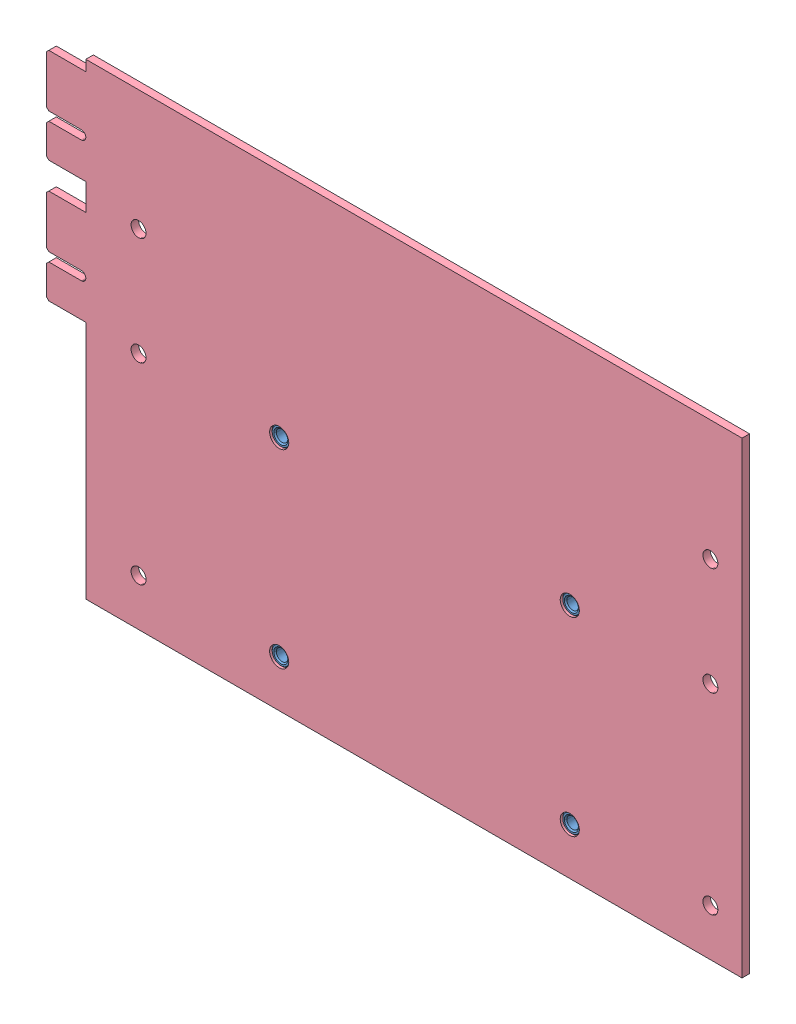
SolidWorks assembly EKO_Miner_BM1366 PCBonly, configuration Défaut. Lengths in mm.
Overall size (148.4 99.75 4.88).
82 component instances, 4 part files, 0 mates.
Components (placement in the parent):
- EKO_Miner_BM1366 PCBonly.step-1: EKO_Miner_BM1366 PCBonly.step [Défaut] at origin size (148.4 99.75 4.88)
  - SMTSO-M3-3ET.step-1: SMTSO-M3-3ET.step [Défaut] at (178 -115 1.25) x (0 0 -1) z (1 0 0) size (4.53 5.56 5.56)
    - 1.step-1: 1.step [Défaut] at origin size (4.53 5.56 5.56)
  - CP_EIA-7343-31_Kemet-D.step-1: CP_EIA-7343-31_Kemet-D.step [Défaut] at (138.6707 -104.934 -0.05) x (0 1 0) z (0 0 -1) size (7.3 4.3 3.1)
    - CP_EIA_7343_31_Kemet_D.step-1: CP_EIA_7343_31_Kemet_D.step [Défaut] at origin size (7.3 4.3 3.1)
  - C_1210_3225Metric.step-1: C_1210_3225Metric.step [Défaut] at (111.58 -61.5 -0.05) x (1 0 0) z (0 0 -1) size (3.2 2.5 2.5)
    - C_1210_3225Metric-1.step-1: C_1210_3225Metric-1.step [Défaut] at origin size (3.2 2.5 2.5)
  - C_1210_3225Metric.step-2: C_1210_3225Metric.step [Défaut] at (111.58 -68.104 -0.05) x (1 0 0) z (0 0 -1) size (3.2 2.5 2.5)
    - C_1210_3225Metric-1.step-1: C_1210_3225Metric-1.step [Défaut] at origin size (3.2 2.5 2.5)
  - CP_EIA-7343-31_Kemet-D.step-2: CP_EIA-7343-31_Kemet-D.step [Défaut] at (90.498 -84.106 -0.05) x (0 -1 0) z (0 0 -1) size (7.3 4.3 3.1)
    - CP_EIA_7343_31_Kemet_D.step-1: CP_EIA_7343_31_Kemet_D.step [Défaut] at origin size (7.3 4.3 3.1)
  - C_1210_3225Metric.step-3: C_1210_3225Metric.step [Défaut] at (208.98 -64.802 -0.05) x (1 0 0) z (0 0 -1) size (3.2 2.5 2.5)
    - C_1210_3225Metric-1.step-1: C_1210_3225Metric-1.step [Défaut] at origin size (3.2 2.5 2.5)
  - C_1210_3225Metric.step-4: C_1210_3225Metric.step [Défaut] at (144.0467 -61.5 -0.05) x (1 0 0) z (0 0 -1) size (3.2 2.5 2.5)
    - C_1210_3225Metric-1.step-1: C_1210_3225Metric-1.step [Défaut] at origin size (3.2 2.5 2.5)
  - C_1210_3225Metric.step-5: C_1210_3225Metric.step [Défaut] at (208.98 -58.2047 -0.05) x (1 0 0) z (0 0 -1) size (3.2 2.5 2.5)
    - C_1210_3225Metric-1.step-1: C_1210_3225Metric-1.step [Défaut] at origin size (3.2 2.5 2.5)
  - CP_EIA-7343-31_Kemet-D.step-3: CP_EIA-7343-31_Kemet-D.step [Défaut] at (154.9414 -84.106 -0.05) x (0 -1 0) z (0 0 -1) size (7.3 4.3 3.1)
    - CP_EIA_7343_31_Kemet_D.step-1: CP_EIA_7343_31_Kemet_D.step [Défaut] at origin size (7.3 4.3 3.1)
  - C_1210_3225Metric.step-6: C_1210_3225Metric.step [Défaut] at (144.0467 -64.802 -0.05) x (1 0 0) z (0 0 -1) size (3.2 2.5 2.5)
    - C_1210_3225Metric-1.step-1: C_1210_3225Metric-1.step [Défaut] at origin size (3.2 2.5 2.5)
  - CP_EIA-7343-31_Kemet-D.step-4: CP_EIA-7343-31_Kemet-D.step [Défaut] at (90.498 -104.934 -0.05) x (0 1 0) z (0 0 -1) size (7.3 4.3 3.1)
    - CP_EIA_7343_31_Kemet_D.step-1: CP_EIA_7343_31_Kemet_D.step [Défaut] at origin size (7.3 4.3 3.1)
  - C_1210_3225Metric.step-7: C_1210_3225Metric.step [Défaut] at (208.98 -61.5 -0.05) x (1 0 0) z (0 0 -1) size (3.2 2.5 2.5)
    - C_1210_3225Metric-1.step-1: C_1210_3225Metric-1.step [Défaut] at origin size (3.2 2.5 2.5)
  - CP_EIA-7343-31_Kemet-D.step-5: CP_EIA-7343-31_Kemet-D.step [Défaut] at (202.512 -104.934 -0.05) x (0 1 0) z (0 0 -1) size (7.3 4.3 3.1)
    - CP_EIA_7343_31_Kemet_D.step-1: CP_EIA_7343_31_Kemet_D.step [Défaut] at origin size (7.3 4.3 3.1)
  - SMTSO-M3-3ET.step-2: SMTSO-M3-3ET.step [Défaut] at (116 -74.5 1.25) x (0 0 -1) z (1 0 0) size (4.53 5.56 5.56)
    - 1.step-1: 1.step [Défaut] at origin size (4.53 5.56 5.56)
  - CP_EIA-7343-31_Kemet-D.step-6: CP_EIA-7343-31_Kemet-D.step [Défaut] at (186.51 -104.934 -0.05) x (0 1 0) z (0 0 -1) size (7.3 4.3 3.1)
    - CP_EIA_7343_31_Kemet_D.step-1: CP_EIA_7343_31_Kemet_D.step [Défaut] at origin size (7.3 4.3 3.1)
  - CP_EIA-7343-31_Kemet-D.step-7: CP_EIA-7343-31_Kemet-D.step [Défaut] at (154.6727 -104.934 -0.05) x (0 1 0) z (0 0 -1) size (7.3 4.3 3.1)
    - CP_EIA_7343_31_Kemet_D.step-1: CP_EIA_7343_31_Kemet_D.step [Défaut] at origin size (7.3 4.3 3.1)
  - C_1210_3225Metric.step-8: C_1210_3225Metric.step [Défaut] at (144.0467 -58.2047 -0.05) x (1 0 0) z (0 0 -1) size (3.2 2.5 2.5)
    - C_1210_3225Metric-1.step-1: C_1210_3225Metric-1.step [Défaut] at origin size (3.2 2.5 2.5)
  - CP_EIA-7343-31_Kemet-D.step-8: CP_EIA-7343-31_Kemet-D.step [Défaut] at (122.502 -104.934 -0.05) x (0 1 0) z (0 0 -1) size (7.3 4.3 3.1)
    - CP_EIA_7343_31_Kemet_D.step-1: CP_EIA_7343_31_Kemet_D.step [Défaut] at origin size (7.3 4.3 3.1)
  - CP_EIA-7343-31_Kemet-D.step-9: CP_EIA-7343-31_Kemet-D.step [Défaut] at (138.758 -84.106 -0.05) x (0 -1 0) z (0 0 -1) size (7.3 4.3 3.1)
    - CP_EIA_7343_31_Kemet_D.step-1: CP_EIA_7343_31_Kemet_D.step [Défaut] at origin size (7.3 4.3 3.1)
  - CP_EIA-7343-31_Kemet-D.step-10: CP_EIA-7343-31_Kemet-D.step [Défaut] at (168.0833 -58.8 -0.05) x (-1 0 0) z (0 0 -1) size (7.3 4.3 3.1)
    - CP_EIA_7343_31_Kemet_D.step-1: CP_EIA_7343_31_Kemet_D.step [Défaut] at origin size (7.3 4.3 3.1)
  - CP_EIA-7343-31_Kemet-D.step-11: CP_EIA-7343-31_Kemet-D.step [Défaut] at (103.15 -58.8 -0.05) x (-1 0 0) z (0 0 -1) size (7.3 4.3 3.1)
    - CP_EIA_7343_31_Kemet_D.step-1: CP_EIA_7343_31_Kemet_D.step [Défaut] at origin size (7.3 4.3 3.1)
  - C_1210_3225Metric.step-9: C_1210_3225Metric.step [Défaut] at (176.5133 -61.5 -0.05) x (1 0 0) z (0 0 -1) size (3.2 2.5 2.5)
    - C_1210_3225Metric-1.step-1: C_1210_3225Metric-1.step [Défaut] at origin size (3.2 2.5 2.5)
  - CP_EIA-7343-31_Kemet-D.step-12: CP_EIA-7343-31_Kemet-D.step [Défaut] at (171.0523 -84.106 -0.05) x (0 -1 0) z (0 0 -1) size (7.3 4.3 3.1)
    - CP_EIA_7343_31_Kemet_D.step-1: CP_EIA_7343_31_Kemet_D.step [Défaut] at origin size (7.3 4.3 3.1)
  - CP_EIA-7343-31_Kemet-D.step-13: CP_EIA-7343-31_Kemet-D.step [Défaut] at (200.55 -58.8 -0.05) x (-1 0 0) z (0 0 -1) size (7.3 4.3 3.1)
    - CP_EIA_7343_31_Kemet_D.step-1: CP_EIA_7343_31_Kemet_D.step [Défaut] at origin size (7.3 4.3 3.1)
  - CP_EIA-7343-31_Kemet-D.step-14: CP_EIA-7343-31_Kemet-D.step [Défaut] at (106.5 -104.934 -0.05) x (0 1 0) z (0 0 -1) size (7.3 4.3 3.1)
    - CP_EIA_7343_31_Kemet_D.step-1: CP_EIA_7343_31_Kemet_D.step [Défaut] at origin size (7.3 4.3 3.1)
  - C_1210_3225Metric.step-10: C_1210_3225Metric.step [Défaut] at (176.5133 -58.2047 -0.05) x (1 0 0) z (0 0 -1) size (3.2 2.5 2.5)
    - C_1210_3225Metric-1.step-1: C_1210_3225Metric-1.step [Défaut] at origin size (3.2 2.5 2.5)
  - C_1210_3225Metric.step-11: C_1210_3225Metric.step [Défaut] at (208.98 -68.104 -0.05) x (1 0 0) z (0 0 -1) size (3.2 2.5 2.5)
    - C_1210_3225Metric-1.step-1: C_1210_3225Metric-1.step [Défaut] at origin size (3.2 2.5 2.5)
  - CP_EIA-7343-31_Kemet-D.step-15: CP_EIA-7343-31_Kemet-D.step [Défaut] at (135.6167 -58.8 -0.05) x (-1 0 0) z (0 0 -1) size (7.3 4.3 3.1)
    - CP_EIA_7343_31_Kemet_D.step-1: CP_EIA_7343_31_Kemet_D.step [Défaut] at origin size (7.3 4.3 3.1)
  - CP_EIA-7343-31_Kemet-D.step-16: CP_EIA-7343-31_Kemet-D.step [Défaut] at (106.6089 -84.106 -0.05) x (0 -1 0) z (0 0 -1) size (7.3 4.3 3.1)
    - CP_EIA_7343_31_Kemet_D.step-1: CP_EIA_7343_31_Kemet_D.step [Défaut] at origin size (7.3 4.3 3.1)
  - SMTSO-M3-3ET.step-3: SMTSO-M3-3ET.step [Défaut] at (116 -115 1.25) x (0 0 -1) z (1 0 0) size (4.53 5.56 5.56)
    - 1.step-1: 1.step [Défaut] at origin size (4.53 5.56 5.56)
  - CP_EIA-7343-31_Kemet-D.step-17: CP_EIA-7343-31_Kemet-D.step [Défaut] at (122.756 -84.106 -0.05) x (0 -1 0) z (0 0 -1) size (7.3 4.3 3.1)
    - CP_EIA_7343_31_Kemet_D.step-1: CP_EIA_7343_31_Kemet_D.step [Défaut] at origin size (7.3 4.3 3.1)
  - SMTSO-M3-3ET.step-4: SMTSO-M3-3ET.step [Défaut] at (178 -74.5 1.25) x (0 0 -1) z (1 0 0) size (4.53 5.56 5.56)
    - 1.step-1: 1.step [Défaut] at origin size (4.53 5.56 5.56)
  - C_1210_3225Metric.step-12: C_1210_3225Metric.step [Défaut] at (111.58 -58.198 -0.05) x (1 0 0) z (0 0 -1) size (3.2 2.5 2.5)
    - C_1210_3225Metric-1.step-1: C_1210_3225Metric-1.step [Défaut] at origin size (3.2 2.5 2.5)
  - CP_EIA-7343-31_Kemet-D.step-18: CP_EIA-7343-31_Kemet-D.step [Défaut] at (187.2715 -84.086 -0.05) x (0 -1 0) z (0 0 -1) size (7.3 4.3 3.1)
    - CP_EIA_7343_31_Kemet_D.step-1: CP_EIA_7343_31_Kemet_D.step [Défaut] at origin size (7.3 4.3 3.1)
  - CP_EIA-7343-31_Kemet-D.step-19: CP_EIA-7343-31_Kemet-D.step [Défaut] at (203.274 -84.106 -0.05) x (0 -1 0) z (0 0 -1) size (7.3 4.3 3.1)
    - CP_EIA_7343_31_Kemet_D.step-1: CP_EIA_7343_31_Kemet_D.step [Défaut] at origin size (7.3 4.3 3.1)
  - C_1210_3225Metric.step-13: C_1210_3225Metric.step [Défaut] at (176.5133 -64.802 -0.05) x (1 0 0) z (0 0 -1) size (3.2 2.5 2.5)
    - C_1210_3225Metric-1.step-1: C_1210_3225Metric-1.step [Défaut] at origin size (3.2 2.5 2.5)
  - CP_EIA-7343-31_Kemet-D.step-20: CP_EIA-7343-31_Kemet-D.step [Défaut] at (170.508 -104.934 -0.05) x (0 1 0) z (0 0 -1) size (7.3 4.3 3.1)
    - CP_EIA_7343_31_Kemet_D.step-1: CP_EIA_7343_31_Kemet_D.step [Défaut] at origin size (7.3 4.3 3.1)
  - C_1210_3225Metric.step-14: C_1210_3225Metric.step [Défaut] at (176.5133 -68.104 -0.05) x (1 0 0) z (0 0 -1) size (3.2 2.5 2.5)
    - C_1210_3225Metric-1.step-1: C_1210_3225Metric-1.step [Défaut] at origin size (3.2 2.5 2.5)
  - C_1210_3225Metric.step-15: C_1210_3225Metric.step [Défaut] at (144.0467 -68.104 -0.05) x (1 0 0) z (0 0 -1) size (3.2 2.5 2.5)
    - C_1210_3225Metric-1.step-1: C_1210_3225Metric-1.step [Défaut] at origin size (3.2 2.5 2.5)
  - C_1210_3225Metric.step-16: C_1210_3225Metric.step [Défaut] at (111.58 -64.802 -0.05) x (1 0 0) z (0 0 -1) size (3.2 2.5 2.5)
    - C_1210_3225Metric-1.step-1: C_1210_3225Metric-1.step [Défaut] at origin size (3.2 2.5 2.5)
  - EKO_Miner_BM1366-13xx_16-01A PCBonly_PCB.step-1: EKO_Miner_BM1366-13xx_16-01A PCBonly_PCB.step [Défaut] at origin size (148.4 99.75 1.6)
